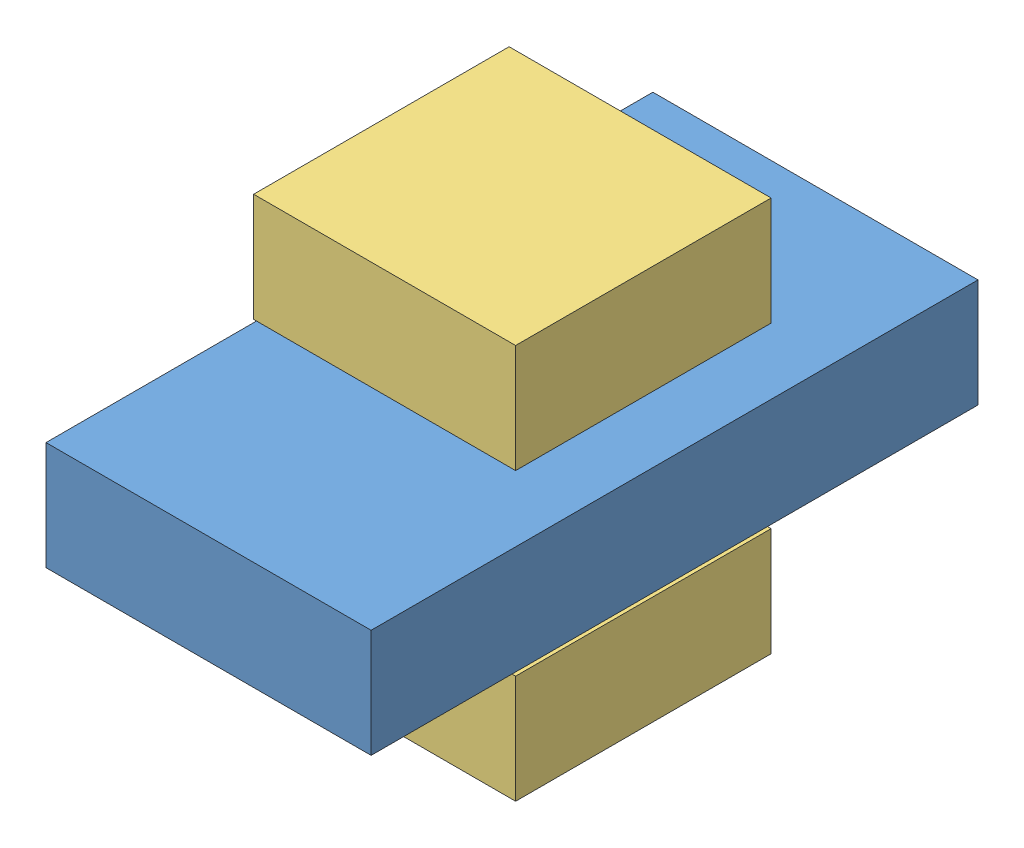
SolidWorks assembly 1119ball, configuration 默认. Lengths in mm.
Overall size (30 36.42 56).
5 component instances, 3 part files, 27 mates.
Components (placement in the parent):
- 插头-1: 插头 [默认] at (2.4385 -1.4574 31) size (30 12.41 56)
- sensor-1: sensor [Default] at (13.9144 -19.6696 56.2851) x (1 0 0) z (0 1 0) size (20.42 20.42 3.21)
- sensor-2: sensor [Default] at (-9.0375 16.7549 56.2851) x (-1 0 0) z (0 -1 0) size (20.42 20.42 3.21)
- sensorbase-1: sensorbase [Default] at (2.5143 16.7549 68.7249) x (0 0 1) z (0 -1 0) size (23.58 24.17 10)
- sensorbase-2: sensorbase [Default] at (2.43 -9.6696 43.2751) x (0 0 -1) z (0 -1 0) size (23.58 24.17 10)
Mates (geometry in assembly coordinates):
- 相切5: tangent anti-aligned: plane of 插头-1 through (2.4385 3.5426 81) normal (0 1 0); sphere of sensor-2
- 相切6: tangent anti-aligned: plane of 插头-1 through (2.4385 3.5426 81) normal (0 1 0); sphere of sensor-2
- 相切7: tangent anti-aligned: plane of 插头-1 through (2.4385 3.5426 81) normal (0 1 0); sphere of sensor-2
- 相切8: tangent: line of 插头-1 through (-12.5615 3.5426 56) axis (1 0 0); sphere of sensor-2
- 相切9: tangent: line of 插头-1 through (2.4385 3.5426 31) axis (0 0 1); sphere of sensor-2
- 相切13: tangent anti-aligned: sphere of sensor-2; line of 插头-1 through (2.4385 3.5426 31) axis (0 0 1)
- 相切14: tangent anti-aligned: plane of 插头-1 through (2.4385 -6.4574 81) normal (0 -1 0); sphere of sensor-1
- 相切15: tangent anti-aligned: plane of 插头-1 through (2.4385 -6.4574 81) normal (0 -1 0); sphere of sensor-1
- 相切16: tangent anti-aligned: plane of 插头-1 through (2.4385 -6.4574 81) normal (0 -1 0); sphere of sensor-1
- 相切17: tangent: line of 插头-1 through (2.4385 -6.4574 81) axis (0 0 -1); sphere of sensor-1
- 相切18: tangent: line of 插头-1 through (2.4385 -6.4574 56) axis (1 0 0); sphere of sensor-1
- 相切19: tangent: line of 插头-1 through (2.4385 -6.4574 81) axis (0 0 -1); sphere of sensor-1
- 相切20: tangent: line of 插头-1 through (2.4385 -6.4574 56) axis (1 0 0); sphere of sensor-1
- 重合2: coincident anti-aligned: plane of sensor-2 through (15.4751 6.7549 18.3302) normal (0 1 0); plane of sensorbase-1 through (2.5143 6.7549 68.7249) normal (0 -1 0)
- 平行1: parallel anti-aligned: plane of 插头-1 through (2.4385 3.5426 81) normal (0 1 0); plane of sensorbase-1 through (2.5143 6.7549 68.7249) normal (0 -1 0)
- 平行2: parallel aligned: plane of sensorbase-1 through (-9.6151 6.7549 44.2123) normal (0 0 -1); plane of 插头-1 through (2.4385 -1.4574 28) normal (0 0 -1)
- 重合5: coincident anti-aligned: plane of sensor-1 through (-10.5982 -9.6696 18.3302) normal (0 -1 0); plane of sensorbase-2 through (2.43 -9.6696 43.2751) normal (0 1 0)
- 平行3: parallel aligned: plane of 插头-1 through (2.4385 3.5426 81) normal (0 1 0); plane of sensorbase-1 through (2.5143 16.7549 68.7249) normal (0 1 0)
- 平行4: parallel aligned: plane of 插头-1 through (2.4385 -6.4574 81) normal (0 -1 0); plane of sensorbase-2 through (2.43 -19.6696 43.2751) normal (0 -1 0)
- 重合8: coincident aligned: plane of sensorbase-1 through (-9.6151 6.7549 44.2123) normal (-1 0 0); plane of sensorbase-2 through (-9.6151 -94.4041 44.2123) normal (-1 0 0)
- 重合9: coincident aligned: plane of sensorbase-1 through (-9.6151 6.7549 44.2123) normal (0 0 -1); plane of sensorbase-2 through (14.5594 -94.4041 44.2123) normal (0 0 -1)
- 重合11: coincident anti-aligned: axis of sensor-2 through (-6.3689 6.7549 56) axis (1 0 0); line of sensorbase-1 through (14.5594 6.7549 56) axis (-1 0 0)
- 同心1: concentric anti-aligned: circle of sensor-1; circle of sensor-2
- 同心2: concentric anti-aligned: circle of sensor-1; circle of sensor-2
- 平行7: parallel aligned: plane of 插头-1 through (2.4385 3.5426 81) normal (0 1 0); plane of sensorbase-1 through (2.5143 16.7549 68.7249) normal (0 1 0)
- 平行8: parallel aligned: plane of 插头-1 through (2.4385 -6.4574 81) normal (0 -1 0); plane of sensorbase-2 through (2.43 -19.6696 43.2751) normal (0 -1 0)
- 重合17: coincident aligned: plane of sensorbase-1 through (14.5594 -67.9797 67.7877) normal (1 0 0); plane of sensorbase-2 through (14.5594 -19.6696 67.7877) normal (1 0 0)
